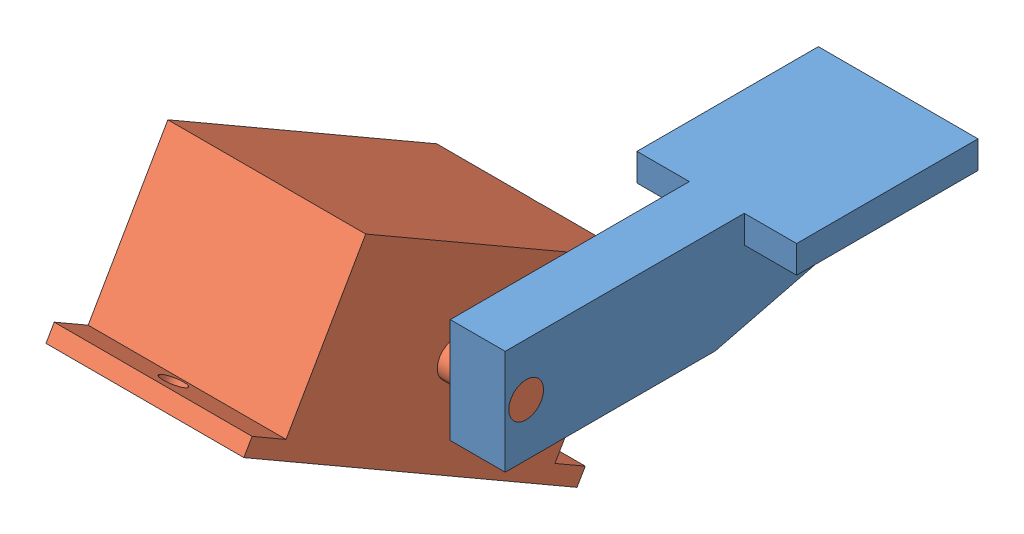
SolidWorks assembly EA3, configuration Default. Lengths in mm.
Overall size (143.05 125.43 222.11).
2 component instances, 2 part files, 2 mates.
Components (placement in the parent):
- EB4_2-1: EB4_2 [Default] at (50.3684 86.3483 116.5793) size (58.1 38.1 153)
- EB4_1-1: EB4_1 [Default] at (-27.6316 86.3483 185.4593) x (0 0.5 0.866025) z (1 0 0) size (140 64 124)
Mates (geometry in assembly coordinates):
- Concentric1: concentric: circle of EB4_2-1; circle of EB4_1-1
- Angle2: planar angle = 0.523599 rad: plane of EB4_2-1 through (70.3684 105.3983 193.0793) normal (0 1 0); plane of EB4_1-1 through (44.3684 28.6489 137.9431) normal (0 0.866025 -0.5)
